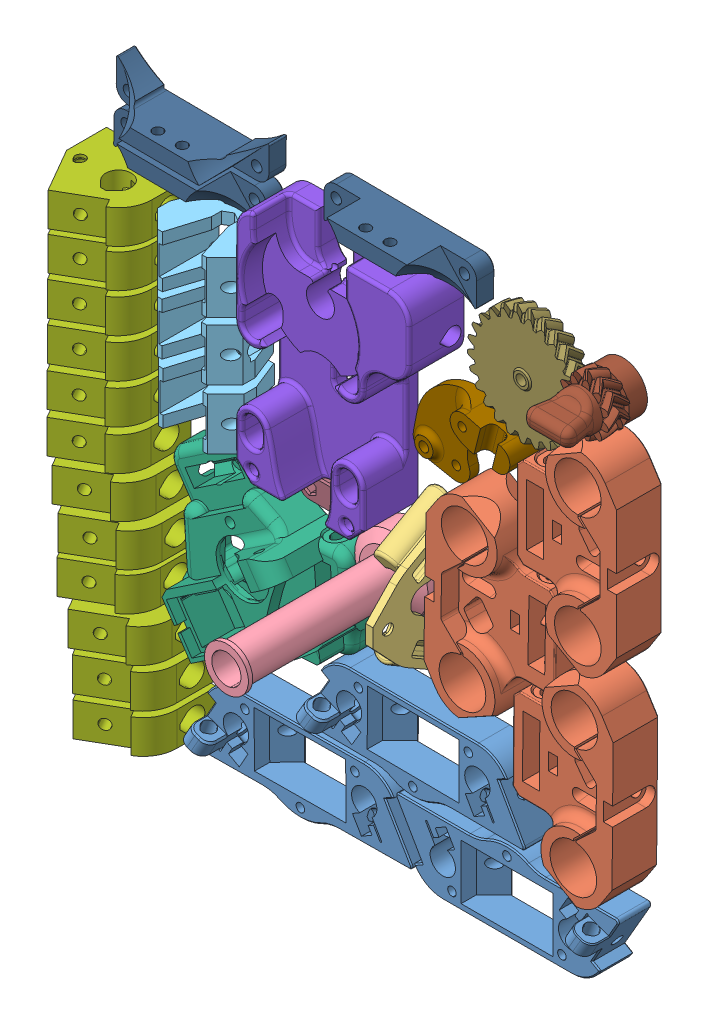
SolidWorks assembly 1200, configuration Default. Lengths in mm.
Overall size (200 200 62.13).
32 component instances, 13 part files, 69 mates.
Components (placement in the parent):
- 1285-1: 1285 [Default] at (-15.706 -76.5235 0) x (-0.999962 -0.008727 0) z (0 0 1) size (72.87 26 17.5)
- 1285-4: 1285 [Default] at (52.0223 -80.4123 0) size (72.87 26 17.5)
- 1285-3: 1285 [Default] at (21.3314 -52.1455 0) x (-0.999962 0.008727 0) z (0 0 1) size (72.87 26 17.5)
- 1304-1: 1304 [Default] at (79.2246 30.5767 0) x (0 1 0) z (0 0 1) size (63.3 37.65 15)
- 1304-2: 1304 [Default] at (41.8124 -1.5384 0) x (-0.017452 -0.999848 0) z (0 0 1) size (63.3 37.65 15)
- 1304-3: 1304 [Default] at (77.9555 -35.8505 0) x (0.008727 0.999962 0) z (0 0 1) size (63.3 37.65 15)
- 1247-1: 1247 [Default] at (26.1467 -10.6362 1) x (-0.008727 -0.999962 0) z (-0.999962 0.008727 0) size (51.6 29.13 11.32)
- 1249-1: 1249 [Default] at (11.1788 -10.2669 0) x (0 0 -1) z (1 0 0) size (62 24 24)
- 1243-6: 1243 [Default] at (-59.407 24.9947 0) size (28 17 20)
- 1243-7: 1243 [Default] at (-59.3239 44.1468 0) size (28 17 20)
- 1243-8: 1243 [Default] at (-59.0482 5.5206 0) size (28 17 20)
- 1301-1: 1301 [Default] at (-31.7128 -27.6559 0) x (0.829038 0.559193 0) z (0 0 1) size (65.4 57.84 25.8)
- 1305-47: 1305 [Default] at (-88.925 36.6309 -7.5) x (0 0 -1) z (-1 0 0) size (27.79 11 28)
- 1305-50: 1305 [Default] at (-88.6498 62.1 -7.5) x (0 0 -1) z (-1 0 0) size (27.79 11 28)
- 1305-52: 1305 [Default] at (-88.7381 49.5085 -7.5) x (0 0 -1) z (-1 0 0) size (27.79 11 28)
- 1306-1: 1306 [Default] at (-8.5291 33.8363 0) size (57.6 77.5 18.81)
- 1305-54: 1305 [Default] at (-80.5744 -78.4427 -7.5) x (0 0 -1) z (-1 0 0) size (27.79 11 28)
- 1309-1: 1309 [Default] at (18.5941 27.7771 3) x (0.190421 0.981703 0) z (0 0 -1) size (28.5 35.3 9.8)
- 1245-5: 1245 [Default] at (-56.694 66.0491 0) x (-0.999962 0.008727 0) z (0 0 1) size (50 13 17)
- 1305-55: 1305 [Default] at (-88.9278 23.7404 -7.5) x (0 0 -1) z (-1 0 0) size (27.79 11 28)
- 1305-57: 1305 [Default] at (-89.0337 10.7108 -7.5) x (0 0 -1) z (-1 0 0) size (27.79 11 28)
- 1305-58: 1305 [Default] at (-89.0155 -2.4957 -7.5) x (0 0 -1) z (-1 0 0) size (27.79 11 28)
- 1305-59: 1305 [Default] at (-87.3177 -15.2479 -7.5) x (0 0 -1) z (-1 0 0) size (27.79 11 28)
- 1305-60: 1305 [Default] at (-85.4727 -28.0042 -7.5) x (0 0 -1) z (-1 0 0) size (27.79 11 28)
- 1305-61: 1305 [Default] at (-85.8251 -40.7145 -7.5) x (0 0 -1) z (-1 0 0) size (27.79 11 28)
- 1305-62: 1305 [Default] at (-82.1271 -53.4629 -7.5) x (0 0 -1) z (-1 0 0) size (27.79 11 28)
- 1305-63: 1305 [Default] at (-80.728 -65.7039 -7.5) x (0 0 -1) z (-1 0 0) size (27.79 11 28)
- 1245-6: 1245 [Default] at (-55.8406 86.8665 0) x (0.999962 -0.008727 0) z (0 0 1) size (50 13 17)
- 1245-7: 1245 [Default] at (12.071 79.4178 0) x (-0.999962 0.008727 0) z (0 0 1) size (50 13 17)
- 1310-1: 1310 [ISO - RH Helical gear 1M 17T 45HA 20PA 12FW ---17A75H50L0.8N] at (79.0133 72.9191 9.5) x (0 0 -1) z (1 0 0) size (25.5 17.1 17.1)
- 1311-1: 1311 [ISO - RH Helical gear 1M 17T 45HA 20PA 12FW ---17A75H50L0.8N] at (52.1349 64.3236 0) x (0 0 1) z (-1 0 0) size (9 36.33 36.3)
- 1320-1: 1320 [Default] at (-6.0209 -3.6773 0) x (0.008727 0.999962 0) z (0 0 1) size (8 22 3.6)
Mates (geometry in assembly coordinates):
- Coincident1: coincident anti-aligned: plane of 1285-1 through (5.2932 -76.3402 0) normal (0 0 -1); plane of assembly through (0 0 0) normal (0 0 1)
- Coincident19: coincident aligned: plane of 1285-1 through (23.6493 28.1454 0) normal (0 0 -1); plane of ? through (71.2682 -68.2496 0) normal (0 0 -1)
- Coincident29: coincident aligned: plane of 1285-1 through (25.2514 30.2008 0) normal (0 0 -1); plane of ? through (1.6814 -76.0194 0) normal (0 0 -1)
- Coincident30: coincident aligned: plane of 1285-1 through (25.2514 30.2008 0) normal (0 0 -1); plane of ? through (-92.3671 -39.4572 0) normal (0 0 -1)
- Coincident31: coincident aligned: plane of 1285-1 through (5.2932 -76.3402 0) normal (0 0 -1); plane of 1285-4 through (31.0223 -80.4123 0) normal (0 0 -1)
- Coincident35: coincident aligned: plane of 1285-1 through (5.2932 -76.3402 0) normal (0 0 -1); plane of 1285-3 through (42.3306 -52.3287 0) normal (0 0 -1)
- Coincident41: coincident aligned: plane of 1285-1 through (23.6493 28.1454 0) normal (0 0 -1); plane of ? through (-50.8118 58.1262 0) normal (0 0 -1)
- Coincident43: coincident aligned: plane of 1285-1 through (-7.1609 -76.8402 0) normal (0 0 -1); plane of ? through (-47.3361 77.4078 0) normal (0 0 -1)
- Coincident44: coincident aligned: plane of 1285-1 through (23.6493 28.1454 0) normal (0 0 -1); plane of ? through (32.1473 -81.3573 0) normal (0 0 -1)
- Coincident48: coincident aligned: plane of 1285-1 through (25.2514 30.2008 0) normal (0 0 -1); plane of ? through (-71.1957 -0.8156 0) normal (0 0 -1)
- Coincident50: coincident aligned: plane of 1285-1 through (25.1493 28.1584 0) normal (0 0 -1); plane of ? through (-18.5975 82.2533 0) normal (0 0 -1)
- Coincident52: coincident aligned: plane of 1285-1 through (5.2932 -76.3402 0) normal (0 0 -1); plane of 1304-2 through (42.1789 19.4584 0) normal (0 0 -1)
- Coincident53: coincident aligned: plane of 1285-1 through (5.2932 -76.3402 0) normal (0 0 -1); plane of 1304-3 through (77.7722 -56.8497 0) normal (0 0 -1)
- Coincident54: coincident aligned: plane of 1285-1 through (25.2514 30.2008 0) normal (0 0 -1); plane of ? through (-71.1957 -0.8156 0) normal (0 0 -1)
- Coincident55: coincident aligned: plane of 1285-1 through (5.2932 -76.3402 0) normal (0 0 -1); plane of 1304-1 through (79.2246 9.5767 0) normal (0 0 -1)
- Coincident56: coincident aligned: plane of 1285-1 through (-7.1609 -76.8402 0) normal (0 0 -1); plane of ? through (35.8059 32.659 0) normal (0 0 -1)
- Coincident57: coincident aligned: plane of 1285-1 through (23.6493 28.1454 0) normal (0 0 -1); plane of ? through (17.5463 -71.5303 0) normal (0 0 -1)
- Coincident58: coincident aligned: plane of 1285-1 through (32.9135 41.1995 0) normal (0 0 -1); plane of ? through (36.2565 -86.3563 0) normal (0 0 -1)
- Coincident60: coincident aligned: plane of 1285-1 through (32.9135 41.1995 0) normal (0 0 -1); plane of ? through (-10.743 10.0798 0) normal (0 0 -1)
- Coincident61: coincident aligned: plane of 1285-1 through (23.6493 28.1454 0) normal (0 0 -1); plane of ? through (53.2972 -22.0845 0) normal (0 0 -1)
- Coincident63: coincident aligned: plane of 1285-1 through (5.2932 -76.3402 0) normal (0 0 -1); plane of 1249-1 through (-0.8212 -10.2669 0) normal (0 0 -1)
- Coincident64: coincident aligned: plane of 1285-1 through (-7.1609 -76.8402 0) normal (0 0 -1); plane of ? through (-41.8079 84.1657 0) normal (0 0 -1)
- Coincident65: coincident aligned: plane of 1285-1 through (25.1493 28.1584 0) normal (0 0 -1); plane of ? through (98.6384 74.7399 0) normal (0 0 -1)
- Coincident67: coincident aligned: plane of 1285-4 through (31.0223 -80.4123 0) normal (0 0 -1); plane of 1243-7 through (-59.3239 44.1468 0) normal (0 0 -1)
- Coincident68: coincident aligned: plane of 1285-4 through (31.0223 -80.4123 0) normal (0 0 -1); plane of 1243-6 through (-59.407 24.9947 0) normal (0 0 -1)
- Coincident69: coincident aligned: plane of ? through (71.2682 -68.2496 0) normal (0 0 -1); plane of 1285-3 through (-19.1237 50.72 0) normal (0 0 -1)
- Coincident71: coincident aligned: plane of 1285-4 through (-18.6053 -3.1899 0) normal (0 0 -1); plane of ? through (80.2014 61.1576 0) normal (0 0 -1)
- Coincident76: coincident aligned: plane of 1285-4 through (-18.6053 -3.1899 0) normal (0 0 -1); plane of ? through (-50.8118 58.1262 0) normal (0 0 -1)
- Coincident77: coincident aligned: plane of 1285-1 through (5.2932 -76.3402 0) normal (0 0 -1); plane of 1285-4 through (31.0223 -80.4123 0) normal (0 0 -1)
- Coincident78: coincident aligned: plane of 1285-4 through (31.0223 -80.4123 0) normal (0 0 -1); plane of 1285-3 through (42.3306 -52.3287 0) normal (0 0 -1)
- Coincident86: coincident aligned: plane of 1304-3 through (77.9104 -56.021 0) normal (0 0 -1); plane of ? through (-87.5278 19.111 0) normal (0 0 -1)
- Coincident87: coincident aligned: plane of 1304-3 through (77.7722 -56.8497 0) normal (0 0 -1); plane of 1305-47 through (-89.925 25.6309 0) normal (0 0 -1)
- Coincident88: coincident aligned: plane of 1304-3 through (77.7722 -56.8497 0) normal (0 0 -1); plane of 1305-50 through (-89.6498 51.1 0) normal (0 0 -1)
- Coincident89: coincident aligned: plane of 1304-3 through (77.7722 -56.8497 0) normal (0 0 -1); plane of 1305-52 through (-89.7381 38.5085 0) normal (0 0 -1)
- Coincident90: coincident aligned: plane of 1304-3 through (-63.1709 -77.7917 0) normal (0 0 -1); plane of ? through (0.1542 72.3591 0) normal (0 0 -1)
- Coincident91: coincident aligned: plane of 1304-3 through (-63.1709 -77.7917 0) normal (0 0 -1); plane of ? through (45.2376 72.7141 0) normal (0 0 -1)
- Coincident92: coincident aligned: plane of 1304-3 through (77.7722 -56.8497 0) normal (0 0 -1); plane of 1301-1 through (-37.8265 0.1851 0) normal (0 0 -1)
- Coincident93: coincident aligned: plane of 1304-3 through (77.7722 -56.8497 0) normal (0 0 -1); plane of 1247-1 through (11.2345 -0.5057 0) normal (0 0 -1)
- Coincident94: coincident aligned: plane of 1304-3 through (77.7722 -56.8497 0) normal (0 0 -1); plane of ? through (41.4802 31.6115 0) normal (0 0 -1)
- Coincident95: coincident aligned: plane of 1304-3 through (77.9104 -56.021 0) normal (0 0 -1); plane of ? through (-47.3361 77.4078 0) normal (0 0 -1)
- Coincident96: coincident aligned: plane of 1304-3 through (74.5066 -55.0203 0) normal (0 0 -1); plane of ? through (35.8059 32.659 0) normal (0 0 -1)
- Coincident97: coincident aligned: plane of 1304-3 through (77.7722 -56.8497 0) normal (0 0 -1); plane of 1243-8 through (-59.0482 5.5206 0) normal (0 0 -1)
- Coincident98: coincident aligned: plane of 1304-3 through (77.7722 -56.8497 0) normal (0 0 -1); plane of 1243-6 through (-59.407 24.9947 0) normal (0 0 -1)
- Coincident99: coincident aligned: plane of 1304-3 through (77.7722 -56.8497 0) normal (0 0 -1); plane of 1243-7 through (-59.3239 44.1468 0) normal (0 0 -1)
- Coincident102: coincident aligned: plane of 1304-1 through (79.2246 9.5767 0) normal (0 0 -1); plane of 1305-54 through (-81.5744 -89.4427 0) normal (0 0 -1)
- Coincident103: coincident aligned: plane of 1304-1 through (79.2246 9.5767 0) normal (0 0 -1); plane of 1305-50 through (-89.6498 51.1 0) normal (0 0 -1)
- Coincident105: coincident aligned: plane of 1306-1 through (-5.3008 40.4247 0) normal (0 0 -1); plane of ? through (89.1989 70.2788 0) normal (0 0 -1)
- Coincident106: coincident aligned: plane of 1306-1 through (-5.3008 40.4247 0) normal (0 0 -1); plane of ? through (76.5337 84.0191 0) normal (0 0 -1)
- Coincident107: coincident aligned: plane of 1301-1 through (-37.8265 0.1851 0) normal (0 0 -1); plane of 1306-1 through (-8.5291 68.9166 0) normal (0 0 -1)
- Coincident108: coincident aligned: plane of 1301-1 through (-37.8265 0.1851 0) normal (0 0 -1); plane of 1309-1 through (17.8087 27.9295 0) normal (0 0 -1)
- Parallel1: parallel anti-aligned: plane of 1305-54 through (-64.5744 -89.4427 13.5) normal (0 -1 0); plane of assembly through (0 0 0) normal (0 1 0)
- Parallel2: parallel aligned: plane of 1305-50 through (-72.6498 51.1 13.5) normal (0 -1 0); plane of 1305-54 through (-64.5744 -89.4427 13.5) normal (0 -1 0)
- Parallel3: parallel aligned: plane of 1305-50 through (-72.6498 51.1 13.5) normal (0 -1 0); plane of 1305-52 through (-72.7381 38.5085 13.5) normal (0 -1 0)
- Parallel4: parallel aligned: plane of 1305-47 through (-72.925 25.6309 13.5) normal (0 -1 0); plane of 1305-52 through (-72.7381 38.5085 13.5) normal (0 -1 0)
- Coincident109: coincident aligned: plane of 1306-1 through (-8.5291 68.9166 0) normal (0 0 -1); plane of 1245-5 through (-32.1143 63.6182 0) normal (0 0 -1)
- Coincident110: coincident aligned: plane of 1306-1 through (-8.5291 68.9166 0) normal (0 0 -1); plane of 1245-6 through (-80.4203 89.2974 0) normal (0 0 -1)
- Coincident111: coincident aligned: plane of 1306-1 through (-8.5291 68.9166 0) normal (0 0 -1); plane of 1245-7 through (36.6508 76.9869 0) normal (0 0 -1)
- Coincident112: coincident aligned: plane of 1306-1 through (-8.5291 68.9166 0) normal (0 0 -1); plane of 1310-1 through (79.0133 72.9191 0) normal (0 0 -1)
- Coincident113: coincident aligned: plane of 1306-1 through (-8.5291 68.9166 0) normal (0 0 -1); plane of 1311-1 through (52.1349 64.3236 0) normal (0 0 -1)
- Coincident114: coincident aligned: plane of 1306-1 through (-8.5291 68.9166 0) normal (0 0 -1); plane of 1305-57 through (-90.0337 -0.2892 0) normal (0 0 -1)
- Coincident115: coincident aligned: plane of 1306-1 through (-8.5291 68.9166 0) normal (0 0 -1); plane of 1305-58 through (-90.0155 -13.4957 0) normal (0 0 -1)
- Coincident116: coincident aligned: plane of 1306-1 through (-8.5291 68.9166 0) normal (0 0 -1); plane of 1305-59 through (-88.3177 -26.2479 0) normal (0 0 -1)
- Coincident117: coincident aligned: plane of 1306-1 through (-8.5291 68.9166 0) normal (0 0 -1); plane of 1305-60 through (-86.4727 -39.0042 0) normal (0 0 -1)
- Coincident118: coincident aligned: plane of 1306-1 through (-8.5291 68.9166 0) normal (0 0 -1); plane of 1305-61 through (-86.8251 -51.7145 0) normal (0 0 -1)
- Coincident119: coincident aligned: plane of 1306-1 through (-8.5291 68.9166 0) normal (0 0 -1); plane of 1305-62 through (-83.1271 -64.4629 0) normal (0 0 -1)
- Coincident120: coincident aligned: plane of 1306-1 through (-8.5291 68.9166 0) normal (0 0 -1); plane of 1305-63 through (-81.728 -76.7039 0) normal (0 0 -1)
- Coincident121: coincident aligned: plane of 1306-1 through (-8.5291 68.9166 0) normal (0 0 -1); plane of 1305-54 through (-81.5744 -89.4427 0) normal (0 0 -1)
- Coincident122: coincident aligned: plane of 1306-1 through (-8.5291 68.9166 0) normal (0 0 -1); plane of 1320-1 through (-20.0203 -3.5551 0) normal (0 0 -1)
- Coincident123: coincident aligned: plane of 1306-1 through (-8.5291 68.9166 0) normal (0 0 -1); plane of 1305-55 through (-89.9278 12.7404 0) normal (0 0 -1)
